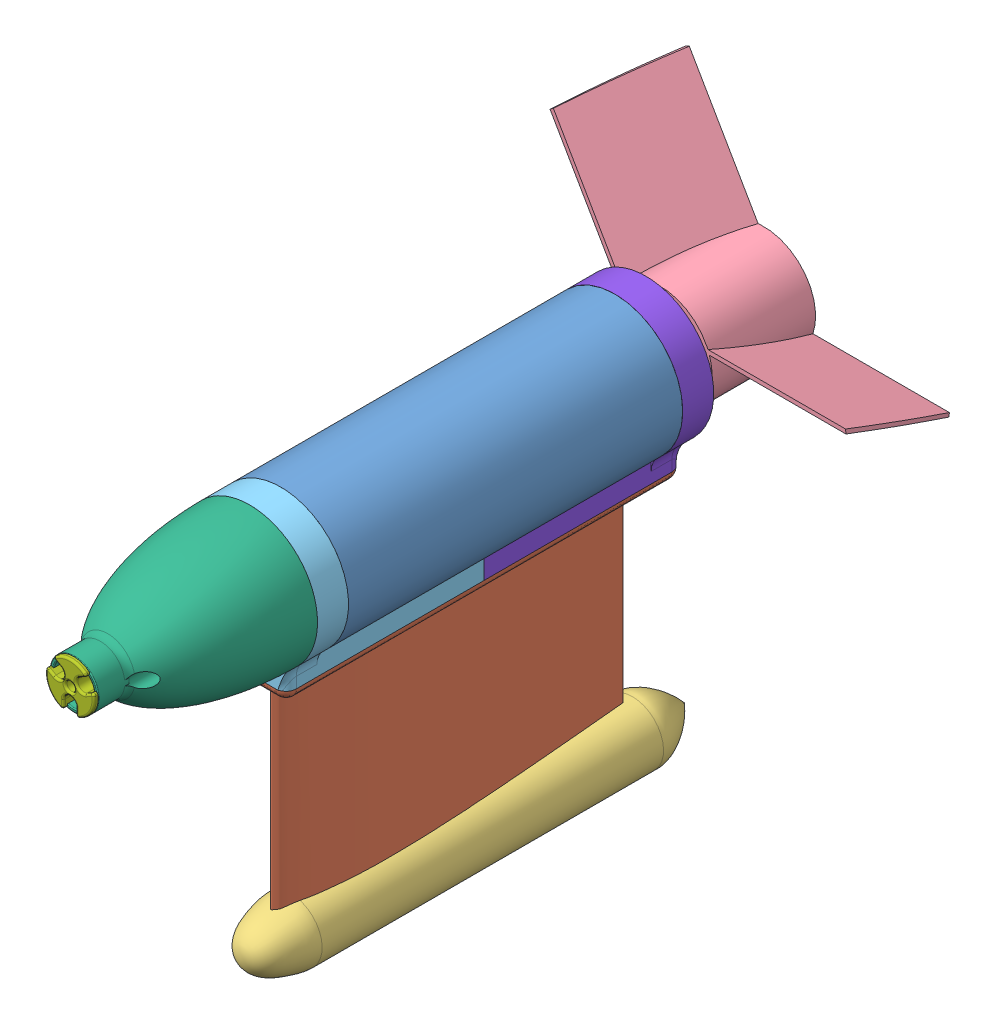
SolidWorks assembly reverse cat assembly, configuration Default. Lengths in mm.
Overall size (143.38 252.55 343.66).
8 component instances, 8 part files, 30 mates.
Components (placement in the parent):
- Flipsky 65161 Motor-2: Flipsky 65161 Motor [Default] at (-233.8297 38 -151.129) x (1 0 0) z (0 0 -1) size (65.5 65.5 241.5)
- reverse cat mast - naca 0012-1: reverse cat mast - naca 0012 [Default] at (-233.8297 0 -151.129) x (0 0 -1) z (-1 0 0) size (192.05 105 35)
- bulb-1: bulb [Default] at (-233.8297 -117 -157.879) size (30.18 30.78 214.08)
- prop-1: prop [Default] at (-233.8297 38 -253.879) x (1 0 0) z (0 1 0) size (143.38 50 164.92)
- reverse cat-3: reverse cat [Default] at (-233.8297 38 -62.879) x (-1 0 0) z (0 -1 0) size (65.5 95.75 71.11)
- nose cone-1: nose cone [Default] at (-233.8297 38 -55.379) x (0 0 1) z (-1 0 0) size (85 69.42 68.43)
- nose plug-1: nose plug [Default] at (-233.8297 38 31.621) x (1 0 0) z (0 1 0) size (23.52 14.81 22.73)
- reverse cat back-3: reverse cat back [Default] at (-233.8297 38 -239.379) x (1 0 0) z (0 -1 0) size (65.5 95.75 71.11)
Mates (geometry in assembly coordinates):
- Coincident1: coincident: plane of ? through (-60605.8469 -37519.4359 -15) normal (0 0 -1); plane of Flipsky 65161 Motor-2 through (-28.2165 86.462 -15) normal (0 0 1)
- Distance1: distance = 8 mm: plane of Flipsky 65161 Motor-2 through (-233.8297 38 -311.879) normal (0 0 -1); plane of prop-1 through (-233.8297 38 -303.879) normal (0 0 -1)
- Concentric6: concentric: circle of Flipsky 65161 Motor-2; circle of prop-1
- Coincident4: coincident: plane of ? through (-60605.8469 -37519.4359 0) normal (0 0 1); plane of assembly through (0 0 0) normal (0 0 1)
- Coincident7: coincident: plane of Flipsky 65161 Motor-2 through (-233.8297 38 -70.379) normal (0 0 1); plane of reverse cat-3 through (-233.8297 38 -70.379) normal (0 0 -1)
- Concentric12: concentric: circle of Flipsky 65161 Motor-2; circle of reverse cat-3
- Concentric13: concentric: circle of reverse cat mast - naca 0012-1; circle of reverse cat-3
- Concentric14: concentric: circle of reverse cat mast - naca 0012-1; circle of reverse cat-3
- Concentric15: concentric: circle of Flipsky 65161 Motor-2; circle of reverse cat-3
- Coincident9: coincident: plane of reverse cat mast - naca 0012-1; plane of ? through (-45.4365 115.7929 -99.0874) normal (0 1 0)
- Concentric16: concentric: circle of reverse cat mast - naca 0012-1; circle of ?
- Concentric17: concentric: circle of reverse cat mast - naca 0012-1; circle of ?
- Coincident11: coincident: plane of reverse cat-3 through (-233.8297 38 -55.379) normal (0 0 1); plane of nose cone-1 through (-233.8297 70.75 -55.379) normal (0 0 -1)
- Concentric20: concentric: circle of nose cone-1; circle of reverse cat-3
- Concentric21: concentric: circle of nose cone-1; circle of reverse cat-3
- Coincident12: coincident: plane of reverse cat-3 through (-221.3297 0 -60.379) normal (0 -1 0); plane of assembly through (0 0 0) normal (0 1 0)
- Coincident13: coincident: plane of nose cone-1 through (-233.8297 38 29.621) normal (0 0 1); plane of nose plug-1 through (-233.8297 38 29.621) normal (0 0 -1)
- Concentric22: concentric: circle of nose plug-1; circle of nose cone-1
- Coincident14: coincident: plane of Flipsky 65161 Motor-2 through (-233.8297 38 -231.879) normal (0 0 -1); plane of reverse cat back-3 through (-233.8297 38 -231.879) normal (0 0 1)
- Concentric23: concentric: circle of reverse cat back-3; circle of Flipsky 65161 Motor-2
- Concentric25: concentric: circle of Flipsky 65161 Motor-2; circle of reverse cat back-3
- Coincident15: coincident: plane of reverse cat mast - naca 0012-1 through (-221.3297 0 -60.379) normal (0 1 0); plane of reverse cat-3 through (-221.3297 0 -60.379) normal (0 -1 0)
- Coincident16: coincident: plane of reverse cat-3 through (-221.3297 0 -60.379) normal (0 -1 0); plane of assembly through (0 0 0) normal (0 1 0)
- Coincident17: coincident: plane of reverse cat mast - naca 0012-1 through (-228.3454 -105 -162.1325) normal (0 -1 0); plane of bulb-1 through (-239.3141 -105 -162.1353) normal (0 1 0)
- Concentric26: concentric: circle of bulb-1; circle of reverse cat mast - naca 0012-1
- Concentric27: concentric: circle of bulb-1; circle of reverse cat mast - naca 0012-1
- Concentric28: concentric: circle of reverse cat mast - naca 0012-1; circle of reverse cat-3
- Concentric29: concentric: circle of reverse cat mast - naca 0012-1; circle of reverse cat-3
- Concentric30: concentric: circle of reverse cat mast - naca 0012-1; cylinder of reverse cat back-3 through (-223.8297 16 -239.379) axis (0 -1 0) radius 1.4
- Concentric31: concentric: circle of reverse cat mast - naca 0012-1; cylinder of reverse cat back-3 through (-243.8297 16 -239.379) axis (0 -1 0) radius 1.4
